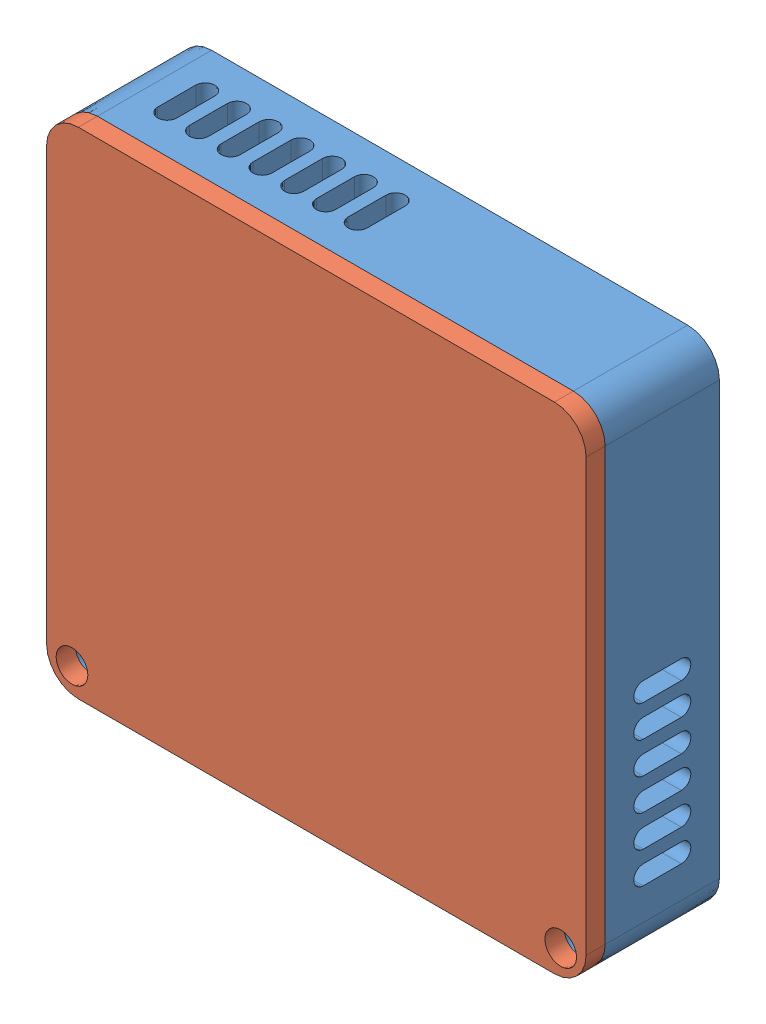
SolidWorks assembly Zero Pi Slimme Meter, configuration Default. Lengths in mm.
Overall size (85 78 21).
2 component instances, 2 part files, 2 mates.
Components (placement in the parent):
- Zero Pi Slimme Meter behuizing-2: Zero Pi Slimme Meter behuizing [Default] at (-12.2749 54.3087 52.9403) size (85 78 18)
- Zero Pi Slimme Meter Deksel-5: Zero Pi Slimme Meter Deksel [Default] at (-12.2749 54.3087 70.9403) size (85 78 6.1)
Mates (geometry in assembly coordinates):
- Coincident2: coincident anti-aligned: plane of Zero Pi Slimme Meter behuizing-2 through (-12.2749 54.3087 70.9403) normal (0 0 1); plane of Deksel-5 through (-12.2749 54.3087 70.9403) normal (0 0 -1)
- Coincident3: coincident aligned: circle of Zero Pi Slimme Meter behuizing-2; circle of Deksel-5
